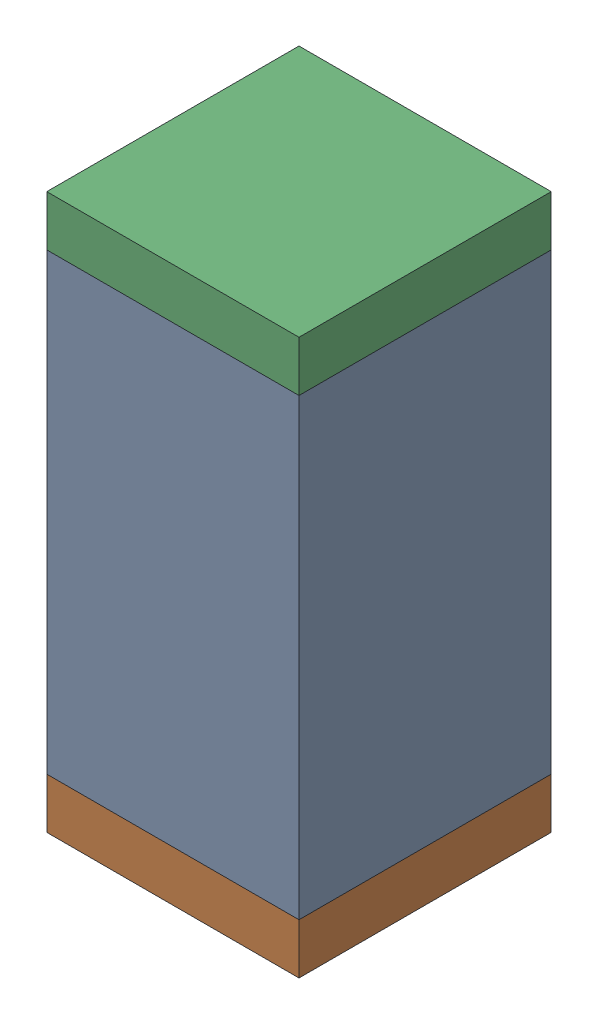
SolidWorks assembly C36, configuration Default. Lengths in mm.
Overall size (0.5 1.1 0.5).
6 component instances, 2 part files, 0 mates.
Components (placement in the parent):
- 791586336-1: 791586336 [Default] at (113.05 32.4 0) size (0.5 0.9 0.5)
  - Extruded_8-1: Extruded_8 [Default] at origin size (0.5 0.9 0.5)
- 810157360-1: 810157360 [Default] at (113.05 31.9 0) size (0.5 0.1 0.5)
  - Extruded_9-1: Extruded_9 [Default] at origin size (0.5 0.1 0.5)
- 810157360-2: 810157360 [Default] at (113.05 32.9 0) size (0.5 0.1 0.5)
  - Extruded_9-1: Extruded_9 [Default] at origin size (0.5 0.1 0.5)
